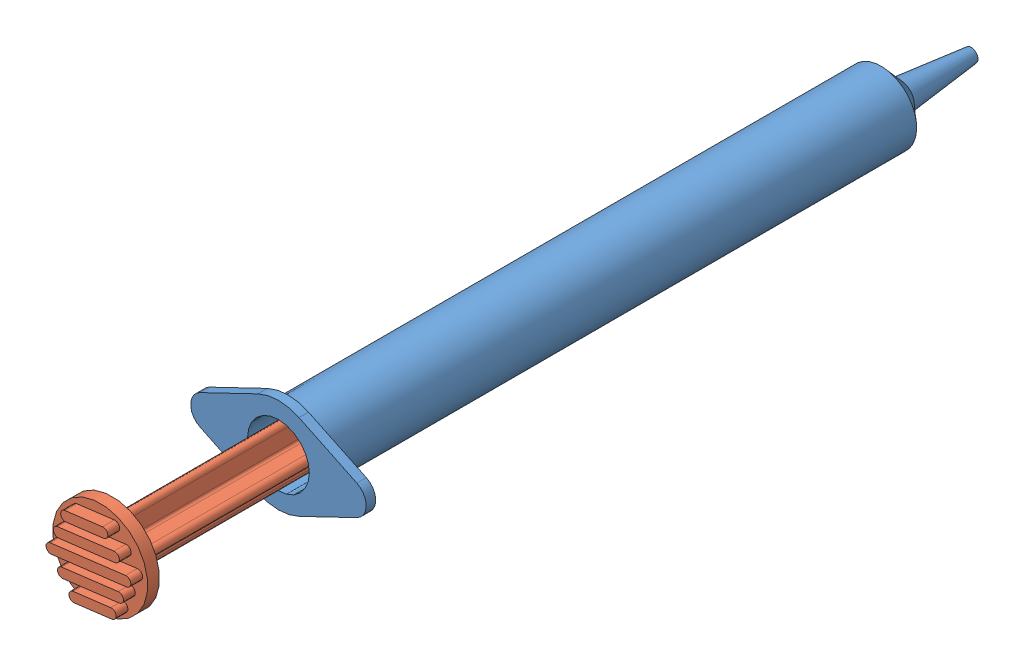
SolidWorks assembly Syringe, configuration Default. Lengths in mm.
Overall size (37 22.32 186.06).
2 component instances, 2 part files, 1 mates.
Components (placement in the parent):
- Syringe-1: Syringe [Default] at (47.3363 93.9514 194.9712) size (37 20 146)
- Plunger-1: Plunger [Default] at (47.3363 93.9514 72.0282) x (-0.123514 0.992343 0) z (0.992343 0.123514 0) size (20 163 20)
Mates (geometry in assembly coordinates):
- Concentric1: concentric aligned: circle of Syringe-1; circle of Plunger-1
